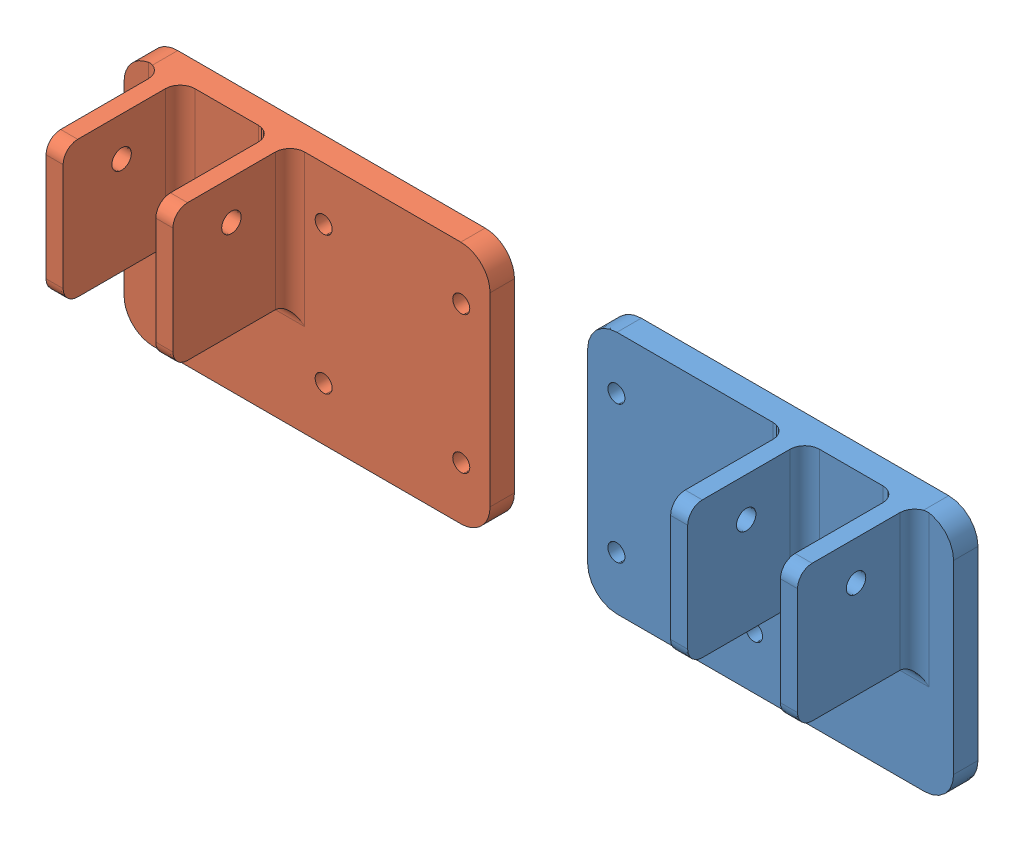
SolidWorks assembly Assem1, configuration 默认. Lengths in mm.
Overall size (170 50 29).
2 component instances, 2 part files, 0 mates.
Components (placement in the parent):
- Lidar_mount_v2_left-1: Lidar_mount_v2_left [默认] at origin size (75 50 29)
- MirrorLidar_mount_v2_left-3: MirrorLidar_mount_v2_left [默认] at (-128 0 0) x (-1 0 0) z (0 0 -1) size (75 50 29)
